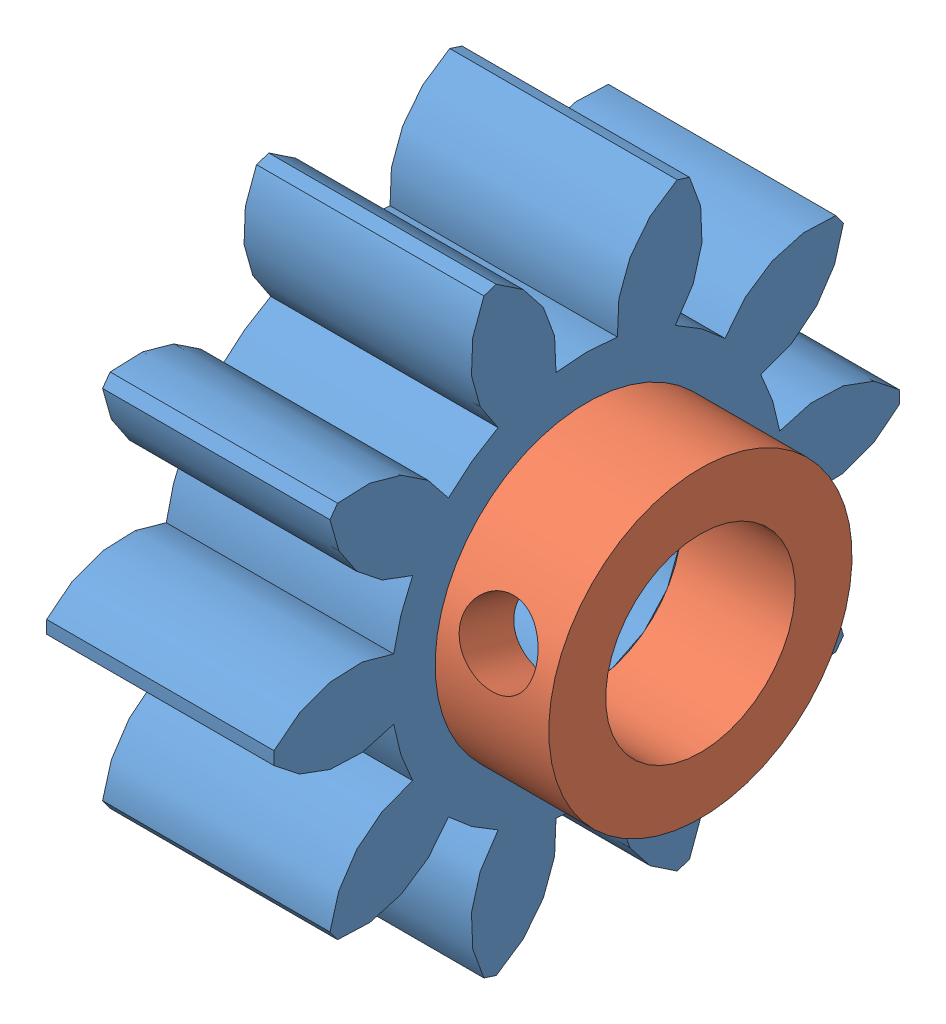
SolidWorks assembly gear_print_2, configuration Default. Lengths in mm.
Overall size (9 15.79 16.5).
2 component instances, 2 part files, 1 mates.
Components (placement in the parent):
- Metric - Spur gear 1.375M 10T 20PA 6FW ---S10N75H50L5N-1: Metric - Spur gear 1.375M 10T 20PA 6FW ---S10N75H50L5N [Metric - Spur gear 1.375M 10T 20PA 6FW ---S10N75H50L5N] at (-2.9954 0.3214 -0.2208) size (6 15.79 16.5)
- gear_space-1: gear_space [Default] at (3.0046 0.3214 -0.2208) x (0 -0.285059 -0.95851) z (0 -0.95851 0.285059) size (8 3 8)
Mates (geometry in assembly coordinates):
- Coincident1: coincident aligned: circle of Metric - Spur gear 1.375M 10T 20PA 6FW ---S10N75H50L5N-1; circle of gear_space-1
